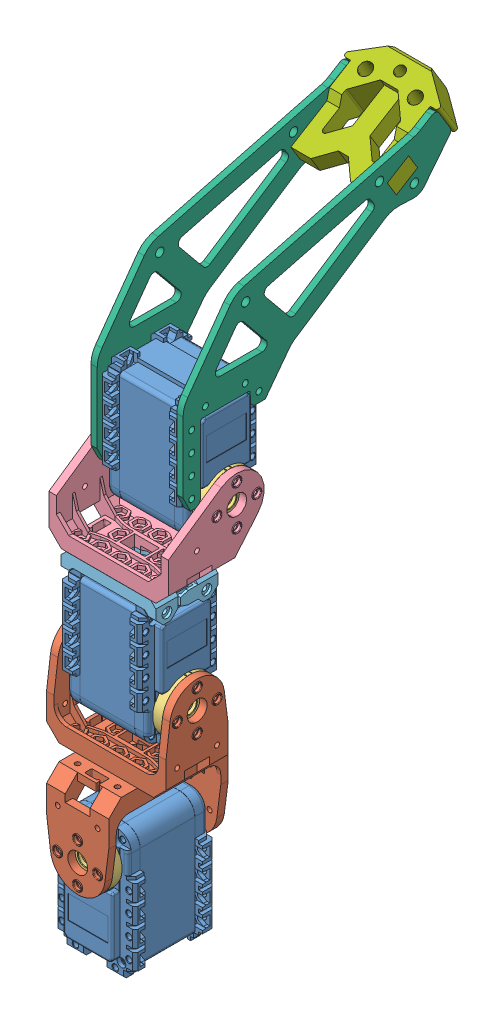
SolidWorks assembly Left_Leg_asm, configuration Default. Lengths in mm.
Overall size (49.4 253.96 139.44).
16 component instances, 7 part files, 6 mates.
Components (placement in the parent):
- ServoBody-1: ServoBody [Default] at (1.7715 35.525 50.0961) size (32 50.04 38.67)
- Coxa_left-1: Coxa_left [Default] at (6.8332 73.9514 95.002) x (1 0 0) z (0 0 -1) size (48.5 75 48.5)
  - F2-1: F2 [Default] at (-5.0617 38.4264 45.8059) size (25 37.5 48.5)
  - F2-2: F2 [Default] at (-5.062 -14.5736 45.8056) x (0 0 -1) z (-1 0 0) size (25 37.5 48.5)
  - ServoHorn-1: ServoHorn [Default] at (-4.932 -14.5736 45.8056) x (0 0 -1) z (1 0 0) size (22 22 6.71)
  - ServoHorn-2: ServoHorn [Default] at (-5.0617 38.4264 45.6759) x (1 0 0) z (0 0 -1) size (22 22 6.71)
- Femur_left-1: Femur_left [Default] at (40.1398 114.3313 34.2621) x (0 0 1) z (-1 0 0) size (42.04 87.04 48.5)
  - F1-1: F1 [Default] at (-0.1082 38.6937 37.4683) size (38.5 34 48.5)
  - F3-1: F3 [Default] at (14.9344 15.6937 37.4686) x (-1 0 0) z (0 0 1) size (25 9 38)
  - ServoBody-1: ServoBody [Default] at (14.9344 -25.8063 37.4686) x (1 0 0) z (0 0 -1) size (32 50.04 38.67)
  - ServoHorn-1: ServoHorn [Default] at (-0.1082 38.6937 37.3383) x (1 0 0) z (0 0 -1) size (22 22 6.71)
- Tibia_left-1: Tibia_left [Default] at (-41.8386 194.8219 31.577) x (0 0 1) z (1 0 0) size (117.15 109.5 38.67)
  - ServoBody-1: ServoBody [Default] at (2.5769 41.7969 45.4101) size (32 50.04 38.67)
  - Tibia side plate-1: Tibia side plate [Défaut] at (2.5769 21.5469 26.9101) x (0 -1 0) z (0 0 1) size (89.6 107.6 2.5)
  - Tibia side plate-2: Tibia side plate [Défaut] at (2.5769 21.5469 61.4101) x (0 -1 0) z (0 0 1) size (89.6 107.6 2.5)
  - Foot-1: Foot [Défaut] at (-63.3454 -35.8706 45.4101) x (0 0 1) z (-0.521616 0.853181 0) size (37.94 40 13)
Mates (geometry in assembly coordinates):
- Concentric1: concentric anti-aligned: cylinder of ServoBody-1 through (1.7715 35.525 63.4961) axis (0 0 1) radius 4.6; cone of Coxa_left-1/ServoHorn-2 through (1.7715 35.525 66.3561) axis (0 0 -1)
- Coincident1: coincident anti-aligned: plane of ServoBody-1 through (-3.0125 30.741 63.4961) normal (0 0 1); plane of Coxa_left-1/ServoHorn-2 through (-2.4019 31.3559 63.4961) normal (0 0 -1)
- Concentric2: concentric anti-aligned: cylinder of Coxa_left-1/ServoHorn-1 through (19.7312 88.525 49.1964) axis (-1 0 0) radius 2.95; cylinder of Femur_left-1/ServoBody-1 through (16.0712 88.525 49.1964) axis (1 0 0) radius 4.6
- Coincident3: coincident anti-aligned: plane of Coxa_left-1/ServoHorn-1 through (16.0712 92.6941 45.023) normal (-1 0 0); plane of Femur_left-1/ServoBody-1 through (16.0712 93.309 44.4124) normal (1 0 0)
- Concentric3: concentric anti-aligned: cylinder of Femur_left-1/ServoHorn-1 through (20.6315 153.025 34.1538) axis (-1 0 0) radius 2.95; cylinder of Tibia_left-1/ServoBody-1 through (16.9715 153.025 34.1538) axis (1 0 0) radius 4.6
- Coincident7: coincident anti-aligned: plane of Femur_left-1/ServoHorn-1 through (16.9715 157.1941 29.9804) normal (-1 0 0); plane of Tibia_left-1/ServoBody-1 through (16.9715 157.809 29.3698) normal (1 0 0)
